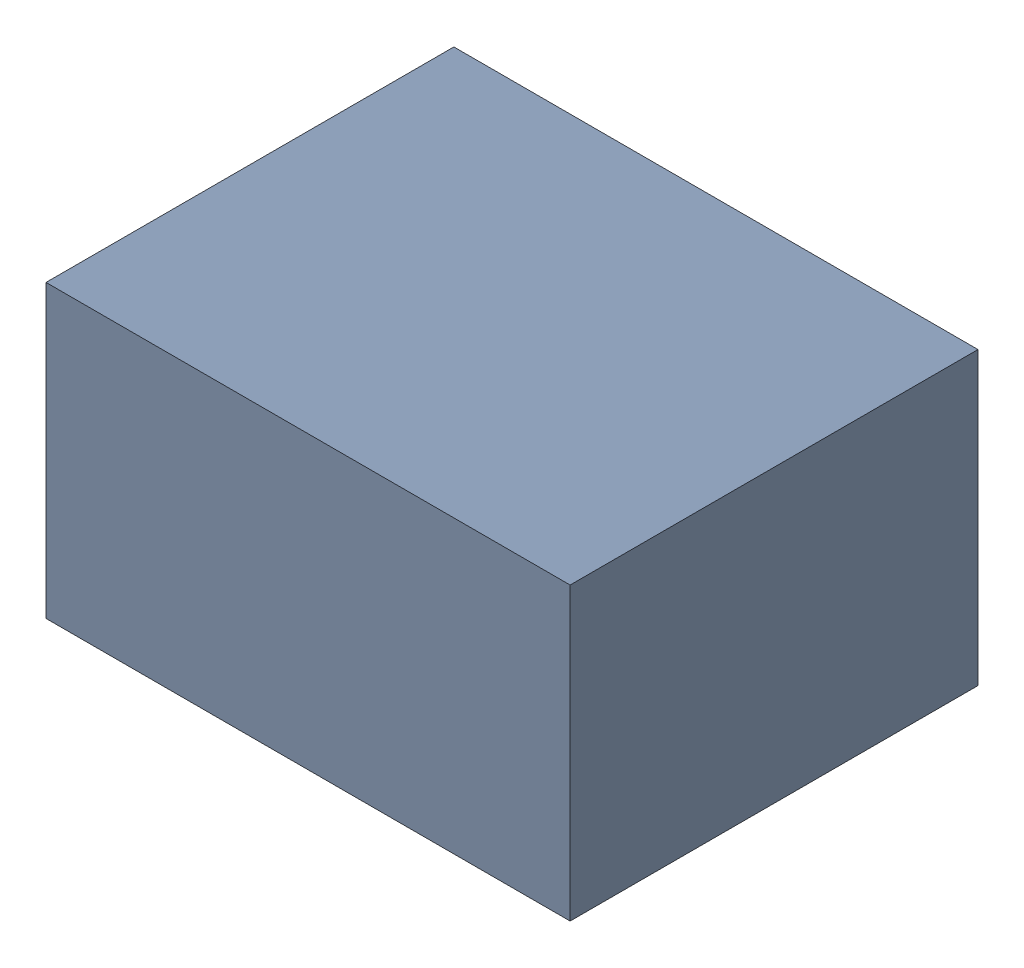
SolidWorks assembly C39, configuration Default. Lengths in mm.
Overall size (1.8 1 1.4).
3 component instances, 2 part files, 0 mates.
Components (placement in the parent):
- 1088884976-1: 1088884976 [Default] at (8.175 22.65 -3.044) size (1.8 1 1.4)
  - Extruded-47-1: Extruded-47 [Default] at origin size (1.8 1 1.4)
- C0603-1: C0603 [Default] at (8.9751 22.2499 -1.644) x (-1 0 0) z (0 -1 0) size (1.6 0.5 0.8)
